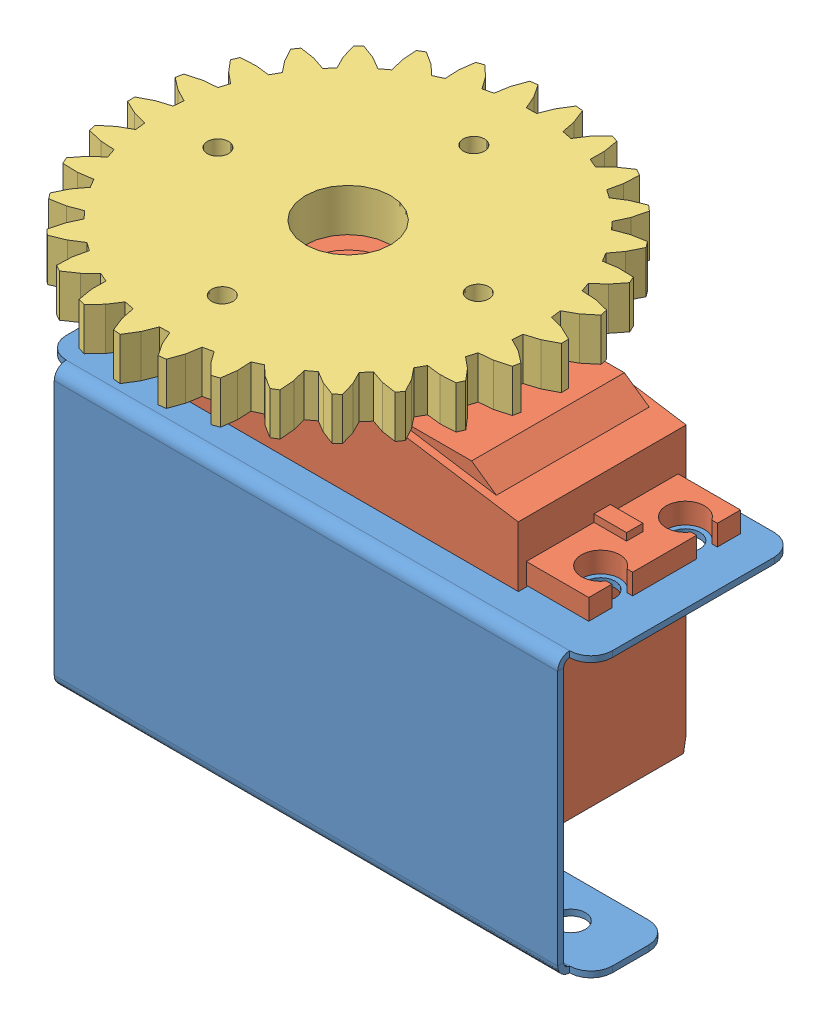
SolidWorks assembly 01 Servo Assembly, configuration Default. Lengths in mm.
Overall size (66.88 50.42 50.66).
3 component instances, 3 part files, 9 mates.
Components (placement in the parent):
- Servo Bracket-1: Servo Bracket [Default] at (0 32.7 -13.4) size (64 32.7 25.4)
- Servo Futaba S3003-1: Servo Futaba S3003 [Default] at (-0.0001 42.1742 -14.3998) x (0 0 1) z (0 -1 0) size (19.69 55.27 37.39)
- Servo Gear (30t)-1: Servo Gear (30t) [Default] at (-54.4002 45.4167 50.1936) x (0.999857 0 -0.016937) z (0.016937 0 0.999857) size (50 5 49.82)
Mates (geometry in assembly coordinates):
- Coincident1: coincident anti-aligned: plane of Servo Bracket-1 through (0 0 -13.4) normal (0 -1 0); plane of assembly through (0 0 0) normal (0 1 0)
- Coincident2: coincident aligned: plane of Servo Bracket-1 through (0 32.7 -13.4) normal (1 0 0); plane of assembly through (0 0 0) normal (1 0 0)
- Coincident3: coincident aligned: plane of Servo Bracket-1 through (0 32.7 0) normal (0 0 1); plane of assembly through (0 0 0) normal (0 0 1)
- Concentric4: concentric anti-aligned: circle of Servo Bracket-1; circle of Servo Futaba S3003-1
- Concentric5: concentric aligned: circle of Servo Bracket-1; circle of Servo Futaba S3003-1
- Coincident8: coincident anti-aligned: plane of Servo Bracket-1 through (0 32.7 -13.4) normal (0 1 0); plane of Servo Futaba S3003-1 through (-27.6353 32.7 -23.2898) normal (0 -1 0)
- Concentric6: concentric aligned: circle of Servo Futaba S3003-1; circle of Servo Bracket-1
- Concentric7: concentric aligned: circle of Servo Bracket-1; circle of Servo Futaba S3003-1
- Concentric8: concentric aligned: circle of Servo Futaba S3003-1; circle of Servo Gear (30t)-1
